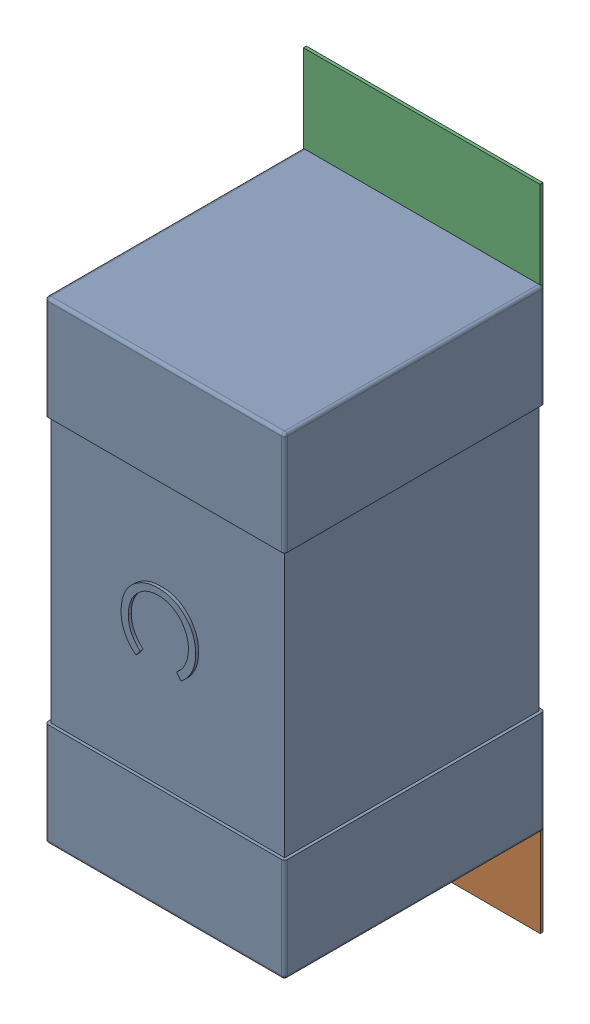
SolidWorks assembly C1, configuration Défaut. Lengths in mm.
Overall size (0.81 2.19 0.88).
5 component instances, 2 part files, 0 mates.
Components (placement in the parent):
- 0603_C-1: 0603_C [Défaut] at (54.0766 -25.1786 0) x (0 -1 0) z (0 0 1) size (1.6 0.81 0.88)
- 8260087904-1: 8260087904 [Défaut] at (54.0766 -26.4286 0) size (0.8 0.6 0.01)
  - Extruded_1211-1: Extruded_1211 [Défaut] at origin size (0.8 0.6 0.01)
- 8260087904-2: 8260087904 [Défaut] at (54.0753 -24.8337 0) size (0.8 0.6 0.01)
  - Extruded_1211-1: Extruded_1211 [Défaut] at origin size (0.8 0.6 0.01)
